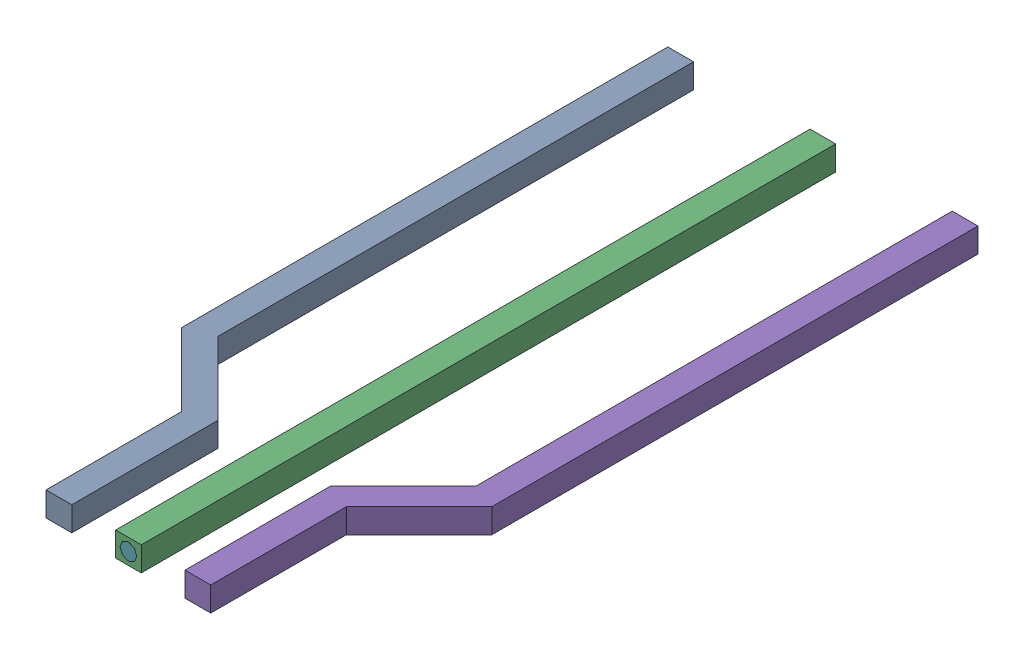
SolidWorks assembly PCB3.step, configuration Default. Lengths in mm.
Overall size (5.68 0.46 12.71).
17 component instances, 5 part files, 0 mates.
Components (placement in the parent):
- Free-Models.step-1: Free-Models.step [Default] at origin size (5.68 0.46 12.71)
  - PCB1.step-1: PCB1.step [Default] at (-1.2706 -0.1276 0) x (1 0 0) z (0 -1 0) size (1.81 12.71 0.46)
    - Free-Models-1.step-1: Free-Models-1.step [Default] at origin size (1.81 12.71 0.46)
      - 523779104.step-1: 523779104.step [Default] at (-0.665 -6.35 -0.35) size (1.81 12.71 0.46)
        - Extruded-43.step-1: Extruded-43.step [Default] at origin size (1.81 12.71 0.46)
    - Board-44.step-1: Board-44.step [Default] at (0 0 -0.2083) size (0.27 0.27 0.21)
  - PCB2.step-1: PCB2.step [Default] at (0.0004 -0.1275 0) x (1 0 0) z (0 -1 0) size (0.47 12.7 0.45)
    - Free-Models-2.step-1: Free-Models-2.step [Default] at origin size (0.47 12.7 0.45)
      - 790454240.step-1: 790454240.step [Default] at (0 -6.35 -0.35) size (0.47 12.7 0.45)
        - Extruded-45.step-1: Extruded-45.step [Default] at origin size (0.47 12.7 0.45)
    - Board-46.step-1: Board-46.step [Default] at (0 0 -0.2083) size (0.27 0.27 0.21)
  - PCB1.step-2: PCB1.step [Default] at (1.2705 0.1276 0) x (-1 0 0) z (0 1 0) size (1.81 12.71 0.46)
    - Free-Models-1.step-1: Free-Models-1.step [Default] at origin size (1.81 12.71 0.46)
      - 523779104.step-1: 523779104.step [Default] at (-0.665 -6.35 -0.35) size (1.81 12.71 0.46)
        - Extruded-43.step-1: Extruded-43.step [Default] at origin size (1.81 12.71 0.46)
    - Board-44.step-1: Board-44.step [Default] at (0 0 -0.2083) size (0.27 0.27 0.21)
- Board-47.step-1: Board-47.step [Default] at (0 0 -0.2083) size (0.31 0.31 0.21)
